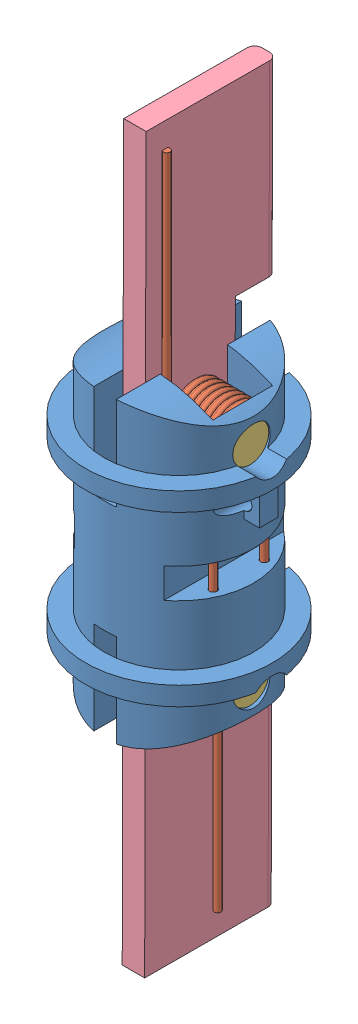
SolidWorks assembly Сборка управления 3-1, configuration Default. Lengths in mm.
Overall size (25 97.94 24.75).
7 component instances, 4 part files, 18 mates.
Components (placement in the parent):
- Ось Рулей 2-1: Ось Рулей 2 [Default] at (11.2417 23.0929 31.1428) size (25 40 24.75)
- Пружина 1-1: Пружина 1 [Default] at (16.1032 37.0366 31.1428) x (1 0 0) z (0 -1 0) size (7.17 7.86 53.5)
- Пружина 1-2: Пружина 1 [Default] at (16.1032 9.1492 31.1428) x (1 0 0) z (0 1 0) size (7.17 7.86 53.5)
- ЗАТЫЧКА-1: ЗАТЫЧКА [Default] at (7.7417 37.0366 31.1428) x (0 0.246907 -0.969039) z (1 0 0) size (5 5 13)
- ЗАТЫЧКА-2: ЗАТЫЧКА [Default] at (7.7417 9.1492 31.1428) x (0 0.246907 -0.969039) z (1 0 0) size (5 5 13)
- Плоскость 3-1-1: Плоскость 3-1 [Default] at (12.7417 37.0366 31.1428) x (0 0.003248 0.999995) z (-1 0 0) size (17.5 41 4)
- Плоскость 3-1-2: Плоскость 3-1 [Default] at (9.7417 9.1492 31.1428) x (0 0.002592 0.999997) z (1 0 0) size (17.5 41 4)
Mates (geometry in assembly coordinates):
- Concentric1: concentric aligned: cylinder of Ось Рулей 2-1 through (7.7417 37.0366 31.1428) axis (1 0 0) radius 2.5; cylinder of Пружина 1-1 through (18.6592 37.0366 31.1428) axis (1 0 0) radius 3
- Concentric2: concentric aligned: cylinder of Ось Рулей 2-1 through (7.7417 9.1492 31.1428) axis (1 0 0) radius 2.5; cylinder of Пружина 1-2 through (18.6592 9.1492 31.1428) axis (1 0 0) radius 3
- Parallel2: parallel aligned: cylinder of Ось Рулей 2-1 through (19.2417 3.0929 27.7279) axis (0 1 0) radius 0.5; cylinder of Пружина 1-2 through (19.2147 9.1492 27.7392) axis (0 1 0) radius 0.4445
- Distance1: distance = 6.75 mm: cylinder of Пружина 1-2 through (12.9917 9.1492 27.7392) axis (0 -1 0) radius 0.4445; plane of Ось Рулей 2-1 through (19.7417 43.7231 35.1428) normal (-1 0 0)
- Parallel3: parallel anti-aligned: cylinder of Ось Рулей 2-1 through (19.2417 3.0929 34.5577) axis (0 1 0) radius 0.5; cylinder of Пружина 1-1 through (19.2147 37.0366 34.5464) axis (0 -1 0) radius 0.4445
- Distance2: distance = 6.75 mm: cylinder of Пружина 1-1 through (12.9917 37.0366 34.5464) axis (0 1 0) radius 0.4445; plane of Ось Рулей 2-1 through (19.7417 22.4628 35.1428) normal (-1 0 0)
- Concentric8: concentric aligned: cylinder of Ось Рулей 2-1 through (7.7417 37.0366 31.1428) axis (1 0 0) radius 2.5; cylinder of Плоскость 3-1 through (9.7417 37.0366 31.1428) axis (1 0 0) radius 2.625
- Coincident1: coincident anti-aligned: plane of Ось Рулей 2-1 through (12.7417 33.0929 21.1428) normal (-1 0 0); plane of Плоскость 3-1 through (12.7417 37.0366 31.1428) normal (1 0 0)
- Concentric9: concentric anti-aligned: cylinder of Ось Рулей 2-1 through (7.7417 9.1492 31.1428) axis (1 0 0) radius 2.5; cylinder of Плоскость 3-2 through (12.7417 9.1492 31.1428) axis (-1 0 0) radius 2.625
- Coincident2: coincident anti-aligned: plane of Ось Рулей 2-1 through (9.7417 13.0929 21.1428) normal (1 0 0); plane of Плоскость 3-2 through (9.7417 9.1492 31.1428) normal (-1 0 0)
- Concentric10: concentric anti-aligned: cylinder of Ось Рулей 2-1 through (7.7417 37.0366 31.1428) axis (1 0 0) radius 2.5; cylinder of ЗАТЫЧКА-1 through (20.7417 37.0366 31.1428) axis (-1 0 0) radius 2.5
- Coincident3: coincident aligned: circle of Ось Рулей 2-1; plane of ЗАТЫЧКА-1 through (7.7417 37.0366 31.1428) normal (-1 0 0)
- Coincident4: coincident anti-aligned: plane of Ось Рулей 2-1 through (7.7417 9.1492 31.1428) normal (1 0 0); plane of ЗАТЫЧКА-2 through (7.7417 9.1492 31.1428) normal (-1 0 0)
- Coincident5: coincident anti-aligned: circle of Ось Рулей 2-1; cylinder of ЗАТЫЧКА-2 through (20.7417 9.1492 31.1428) axis (-1 0 0) radius 2.5
- Concentric11: concentric anti-aligned: cylinder of ЗАТЫЧКА-1 through (20.7417 37.0366 31.1428) axis (-1 0 0) radius 2.5; cylinder of Плоскость 3-1-1 through (9.7417 37.0366 31.1428) axis (1 0 0) radius 2.625
- Coincident6: coincident anti-aligned: plane of Ось Рулей 2-1 through (9.7417 33.0929 21.1428) normal (1 0 0); plane of Плоскость 3-1-1 through (9.7417 37.0366 31.1428) normal (-1 0 0)
- Concentric12: concentric aligned: cylinder of ЗАТЫЧКА-2 through (20.7417 9.1492 31.1428) axis (-1 0 0) radius 2.5; cylinder of Плоскость 3-1-2 through (12.7417 9.1492 31.1428) axis (-1 0 0) radius 2.625
- Coincident7: coincident anti-aligned: plane of Ось Рулей 2-1 through (9.7417 13.0929 21.1428) normal (1 0 0); plane of Плоскость 3-1-2 through (9.7417 9.1492 31.1428) normal (-1 0 0)
